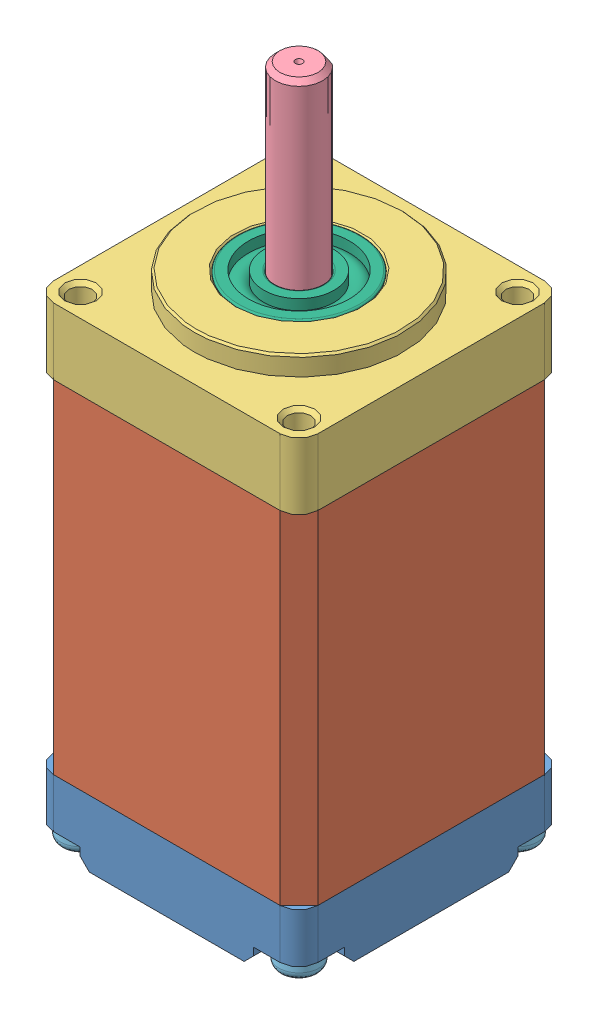
SolidWorks assembly Nema_11_motor_51mm, configuration По умолчанию. Lengths in mm.
Overall size (27.85 71.01 27.85).
10 component instances, 6 part files, 20 mates.
Components (placement in the parent):
- bottom_nema11-1: bottom_nema11 [По умолчанию] at origin size (27.85 7 27.85)
- middle_51_nema11-1: middle_51_nema11 [По умолчанию] at (0 7 0) size (27.85 36 27.85)
- top_nema11-1: top_nema11 [По умолчанию] at (0 43 0) size (27.85 9 27.85)
- shaft_51_nema11-1: shaft_51_nema11 [По умолчанию] at origin size (5 71 5)
- screw_51_nema11-1: screw_51_nema11 [По умолчанию] at (-11.5 1.8 -11.5) size (4.2 45.81 4.2)
- screw_51_nema11-8: screw_51_nema11 [По умолчанию] at (-11.5 1.8 11.5) size (4.2 45.81 4.2)
- screw_51_nema11-9: screw_51_nema11 [По умолчанию] at (11.5 1.8 -11.5) size (4.2 45.81 4.2)
- screw_51_nema11-10: screw_51_nema11 [По умолчанию] at (11.5 1.8 11.5) size (4.2 45.81 4.2)
- instrument ball bearing_68_iso-1: instrument ball bearing_68_iso [ISO 1224 - 190513 - R,Full,SI,NC,Full_68] at (0 50 0) x (0 1 0) z (0 0 1) size (4 13 13)
- instrument ball bearing_68_iso-2: instrument ball bearing_68_iso [ISO 1224 - 190513 - R,Full,SI,NC,Full_68] at (0 3.8 0) x (0 -1 0) z (0 0 1) size (4 13 13)
Mates (geometry in assembly coordinates):
- Совпадение1: coincident anti-aligned: plane of bottom_nema11-1 through (0 7 0) normal (0 1 0); plane of middle_51_nema11-1 through (0 7 0) normal (0 -1 0)
- Совпадение2: coincident aligned: plane of bottom_nema11-1 through (13.925 7 0) normal (1 0 0); plane of middle_51_nema11-1 through (13.925 43 13.925) normal (1 0 0)
- Совпадение3: coincident aligned: plane of bottom_nema11-1 through (0 7 13.925) normal (0 0 1); plane of middle_51_nema11-1 through (-13.925 43 13.925) normal (0 0 1)
- Концентричный1: concentric aligned: cylinder of bottom_nema11-1 through (11.5 7 11.5) axis (0 -1 0) radius 1.25; cylinder of top_nema11-1 through (11.5 50 11.5) axis (0 -1 0) radius 1.25
- Концентричный2: concentric aligned: cylinder of bottom_nema11-1 through (-11.5 7 -11.5) axis (0 -1 0) radius 1.25; cylinder of top_nema11-1 through (-11.5 50 -11.5) axis (0 -1 0) radius 1.25
- Совпадение4: coincident anti-aligned: plane of middle_51_nema11-1 through (0 43 0) normal (0 1 0); plane of top_nema11-1 through (0 43 0) normal (0 -1 0)
- Концентричный3: concentric aligned: cylinder of middle_51_nema11-1 through (0 43 0) axis (0 -1 0) radius 2.5; cylinder of shaft_51_nema11-1 through (0 71 0) axis (0 -1 0) radius 2.5
- Совпадение5: coincident aligned: plane of bottom_nema11-1 through (0 0 0) normal (0 -1 0); plane of shaft_51_nema11-1 through (0 0 0) normal (0 -1 0)
- Концентричный4: concentric aligned: cylinder of bottom_nema11-1 through (-11.5 7 -11.5) axis (0 -1 0) radius 1.25; cylinder of screw_51_nema11-1 through (-11.5 45.8 -11.5) axis (0 -1 0) radius 1.25
- Совпадение6: coincident anti-aligned: plane of bottom_nema11-1 through (0 1.8 0) normal (0 -1 0); plane of screw_51_nema11-1 through (-11.5 1.8 -11.5) normal (0 1 0)
- Концентричный6: concentric aligned: cylinder of bottom_nema11-1 through (-11.5 7 11.5) axis (0 -1 0) radius 1.25; cylinder of screw_51_nema11-8 through (-11.5 45.8 11.5) axis (0 -1 0) radius 1.25
- Совпадение7: coincident anti-aligned: plane of bottom_nema11-1 through (0 1.8 0) normal (0 -1 0); plane of screw_51_nema11-8 through (-11.5 1.8 11.5) normal (0 1 0)
- Концентричный7: concentric aligned: cylinder of bottom_nema11-1 through (11.5 7 -11.5) axis (0 -1 0) radius 1.25; cylinder of screw_51_nema11-9 through (11.5 45.8 -11.5) axis (0 -1 0) radius 1.25
- Совпадение8: coincident anti-aligned: plane of bottom_nema11-1 through (0 1.8 0) normal (0 -1 0); plane of screw_51_nema11-9 through (11.5 1.8 -11.5) normal (0 1 0)
- Концентричный8: concentric aligned: cylinder of bottom_nema11-1 through (11.5 7 11.5) axis (0 -1 0) radius 1.25; cylinder of screw_51_nema11-10 through (11.5 45.8 11.5) axis (0 -1 0) radius 1.25
- Совпадение9: coincident anti-aligned: plane of bottom_nema11-1 through (0 1.8 0) normal (0 -1 0); plane of screw_51_nema11-10 through (11.5 1.8 11.5) normal (0 1 0)
- Концентричный9: concentric anti-aligned: cylinder of top_nema11-1 through (0 50 0) axis (0 -1 0) radius 6.5; cylinder of instrument ball bearing_68_iso-1 through (0 29.3625 0) axis (0 1 0) radius 6.5
- Совпадение10: coincident aligned: plane of top_nema11-1 through (0 52 0) normal (0 1 0); plane of instrument ball bearing_68_iso-1 through (-6.3 52 0) normal (0 1 0)
- Концентричный10: concentric anti-aligned: cylinder of bottom_nema11-1 through (0 2 0) axis (0 1 0) radius 6.5; cylinder of instrument ball bearing_68_iso-2 through (0 24.4375 0) axis (0 -1 0) radius 6.5
- Совпадение11: coincident anti-aligned: circle of bottom_nema11-1; plane of instrument ball bearing_68_iso-2 through (6.3 1.8 0) normal (0 -1 0)
